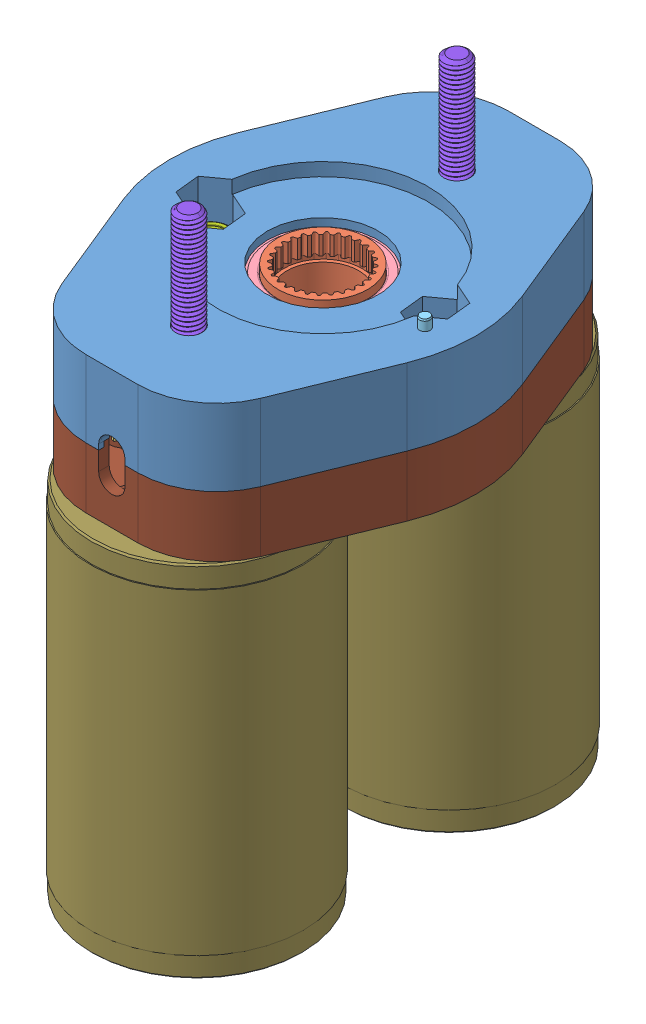
SolidWorks assembly 217-3141-BAG STEP, configuration Default. Lengths in mm.
Overall size (58 114.72 88.18).
24 component instances, 13 part files, 0 mates.
Components (placement in the parent):
- 217-3141-001 Rev1-1: 217-3141-001 Rev1 [Default] x (0 0 1) z (-1 0 0) size (80 14.5 58)
- 217-3141-007 Rev1_30T 32DP-1: 217-3141-007 Rev1_30T 32DP [Default] at (0 -7.06 0) x (0 -1 0) z (-0.999183 0 0.040426) size (22.38 25.55 25.47)
- 217-3141-006 Rev1_30T 32DP-1: 217-3141-006 Rev1_30T 32DP [Default] at (0 -9.85 -23.8887) x (-0.095925 0 -0.995389) z (0 -1 0) size (25.47 25.55 10)
- 217-3141-006 Rev1_30T 32DP-2: 217-3141-006 Rev1_30T 32DP [Default] at (0 -9.85 23.8887) x (-0.001725 0 0.999999) z (0 -1 0) size (25.47 25.55 10)
- 217-2741-1: 217-2741 [Default] at (0 2.75 0) x (0 -1 0) z (-0.999445 0 -0.033298) size (5 26 26)
- 217-2741-2: 217-2741 [Default] at (0 -13.25 0) x (0 -1 0) z (-0.537831 0 0.843053) size (5 26 26)
- PINL-M020-006-S-1: PINL-M020-006-S [Default] at (22.7445 5.75 3.4184) x (0 1 0) z (-0.890225 0 0.455522) size (6 2 2)
- SSS1032-0188-ZB-1: SSS1032-0188-ZB [Default] at (-0.3489 -11.725 -27.5094) x (-0.758755 -0.647259 0.073121) z (0.095925 0 0.995389) size (4.91 4.91 5.06)
- SSS1032-0188-ZB-2: SSS1032-0188-ZB [Default] at (-0.0063 -11.725 27.5262) x (0.762269 -0.647259 0.001315) z (0.001725 0 -0.999999) size (4.91 4.91 5.06)
- NUT-832-NYLOCK-1: NUT-832-NYLOCK [Default] at (19.244 -4.75 -2.0226) x (0.913545 0 0.406737) z (-0.406737 0 0.913545) size (10.2 4.9 8.12)
- NUT-832-NYLOCK-2: NUT-832-NYLOCK [Default] at (-19.244 -4.75 2.0226) x (0.912648 0 0.408747) z (-0.408747 0 0.912648) size (10.2 4.9 8.12)
- 91251A346_91251A346-1: 91251A346_91251A346 [Default] at (0 25.975 25.4) x (1 0 0) z (0 1 0) size (7.92 7.92 27.28)
- 91251A346_91251A346-2: 91251A346_91251A346 [Default] at (0 25.975 -25.4) x (1 0 0) z (0 1 0) size (7.92 7.92 27.28)
- SSA_SSAM4-0010ZC-1: SSA_SSAM4-0010ZC [Default] at (12.5 -17.25 -23.8887) size (7 14 7)
- SSA_SSA0832-0750ZC-1: SSA_SSA0832-0750ZC [Default] at (19.244 -19.25 -2.0226) x (-0.091926 0 -0.995766) z (-0.995766 0 0.091926) size (6.73 23.11 6.73)
- SSA_SSA0832-0750ZC-2: SSA_SSA0832-0750ZC [Default] at (-19.244 -19.25 2.0226) x (-0.18632 0 -0.982489) z (-0.982489 0 0.18632) size (6.73 23.11 6.73)
- SSA_SSAM4-0010ZC-2: SSA_SSAM4-0010ZC [Default] at (-12.5 -17.25 23.8887) x (0.677756 0 0.735287) z (-0.735287 0 0.677756) size (7 14 7)
- SSA_SSAM4-0010ZC-3: SSA_SSAM4-0010ZC [Default] at (12.5 -17.25 23.8887) x (0.994338 0 -0.106265) z (0.106265 0 0.994338) size (7 14 7)
- SSA_SSAM4-0010ZC-4: SSA_SSAM4-0010ZC [Default] at (-12.5 -17.25 -23.8887) x (0.537906 0 -0.843005) z (0.843005 0 0.537906) size (7 14 7)
- 217-3141-002 Rev2-1: 217-3141-002 Rev2 [Default] at (0 -13 0) x (0 0 1) z (0 1 0) size (80 58 12.5)
- 217-3351-1: 217-3351 [Default] at (0 -19.25 -23.8887) x (1 0 0) z (0 1 0) size (40.4 40.4 81.5)
- 217-3351-2: 217-3351 [Default] at (0 -19.25 23.8887) x (1 0 0) z (0 1 0) size (40.4 40.4 81.5)
- 217-2625-011 Rev1-1: 217-2625-011 Rev1 [Default] at (0 -11.1 -23.8887) x (0.095925 0 0.995389) z (-0.995389 0 0.095925) size (8.01 7.5 7.94)
- 217-2625-011 Rev1-2: 217-2625-011 Rev1 [Default] at (0 -11 23.8887) x (-0.964857 0 0.262777) z (-0.262777 0 -0.964857) size (8.01 7.5 7.94)
